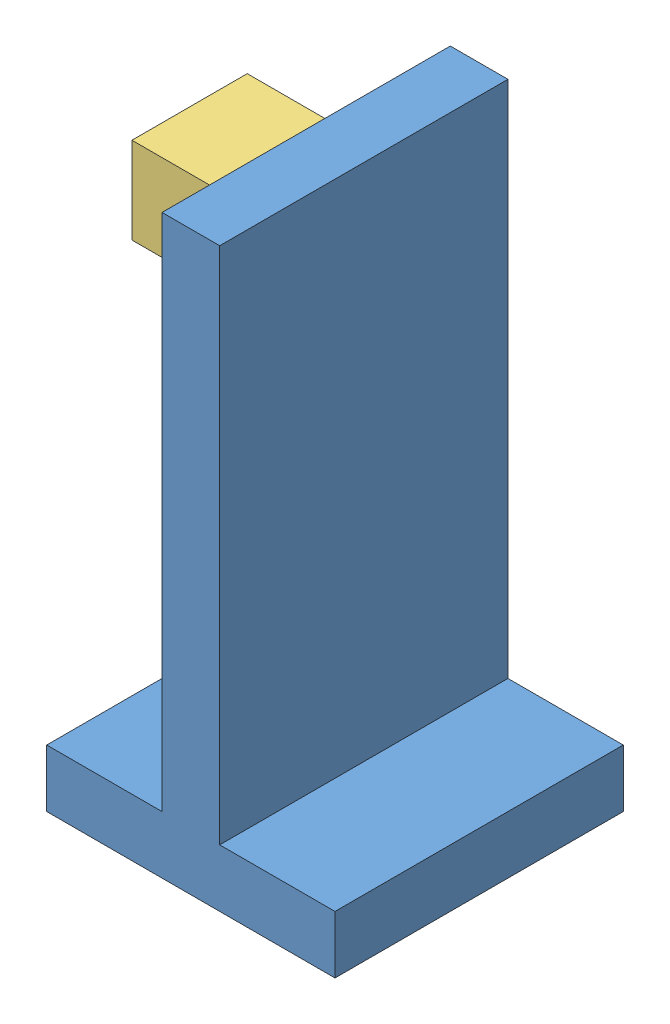
SolidWorks assembly Assemblage des pièces, configuration Défaut. Lengths in mm.
Overall size (500 1000 500).
4 component instances, 4 part files, 9 mates.
Components (placement in the parent):
- corps-1: corps [Défaut] at (-254.2121 -469.4622 750) size (500 1000 500)
- porte-1: porte [Défaut] at (-67.2121 -201.7817 1150) x (0 0 -1) z (1 0 0) size (300 350 3)
- boite pour electronique et moteur-1: boite pour electronique et moteur [Défaut] at (-54.2121 315.1289 902.2084) x (0 0 1) z (-1 0 0) size (200 150 200)
- moteur continu-1: moteur continu [Défaut] at (-166.6979 354.1289 1008.1139) x (0 0 -1) z (1 0 0) size (242.7 150 120)
Mates (geometry in assembly coordinates):
- Coïncidente5: coincident: plane of assembly; plane of assembly; plane of corps-1 through (-64.2121 230.5378 1150) normal (0 0 -1); plane of porte-1 through (-64.2121 -201.7817 1150) normal (0 0 1)
- Coïncidente6: coincident: plane of assembly; plane of assembly; plane of corps-1 through (-64.2121 230.5378 850) normal (0 0 1); plane of porte-1 through (-64.2121 -201.7817 850) normal (0 0 -1)
- Coïncidente7: coincident: line of assembly; line of assembly; line of corps-1 through (-64.2121 230.5378 850) axis (0 -1 0); line of porte-1 through (-64.2121 -201.7817 850) axis (0 1 0)
- Coïncidente9: coincident: plane of assembly; plane of assembly; plane of corps-1 through (-54.2121 530.5378 1250) normal (-1 0 0); plane of boite pour electronique et moteur-1 through (-54.2121 315.1289 902.2084) normal (1 0 0)
- Parallèle1: parallel: line of assembly; plane of assembly; line of corps-1 through (-54.2121 530.5378 1250) axis (0 0 -1); plane of boite pour electronique et moteur-1 through (-254.2121 465.1289 902.2084) normal (0 1 0)
- Coïncidente10: coincident: plane of assembly; plane of assembly; plane of boite pour electronique et moteur-1 through (-254.2121 325.1289 912.2084) normal (0 1 0); plane of moteur continu-1 through (-107.6979 325.1289 984.6139) normal (0 -1 0)
- Verrouiller3: lock: unknown of corps-1; unknown of boite pour electronique et moteur-1
- Parallèle8: parallel: plane of assembly; line of assembly; plane of boite pour electronique et moteur-1 through (-254.2121 325.1289 1092.2084) normal (0 0 -1); line of moteur continu-1 through (-156.6979 327.1289 1031.6139) axis (1 0 0)
- Coïncidente20: coincident: plane of assembly; plane of assembly; plane of boite pour electronique et moteur-1 through (-254.2121 325.1289 912.2084) normal (0 1 0); plane of moteur continu-1 through (-107.6979 325.1289 984.6139) normal (0 -1 0)
